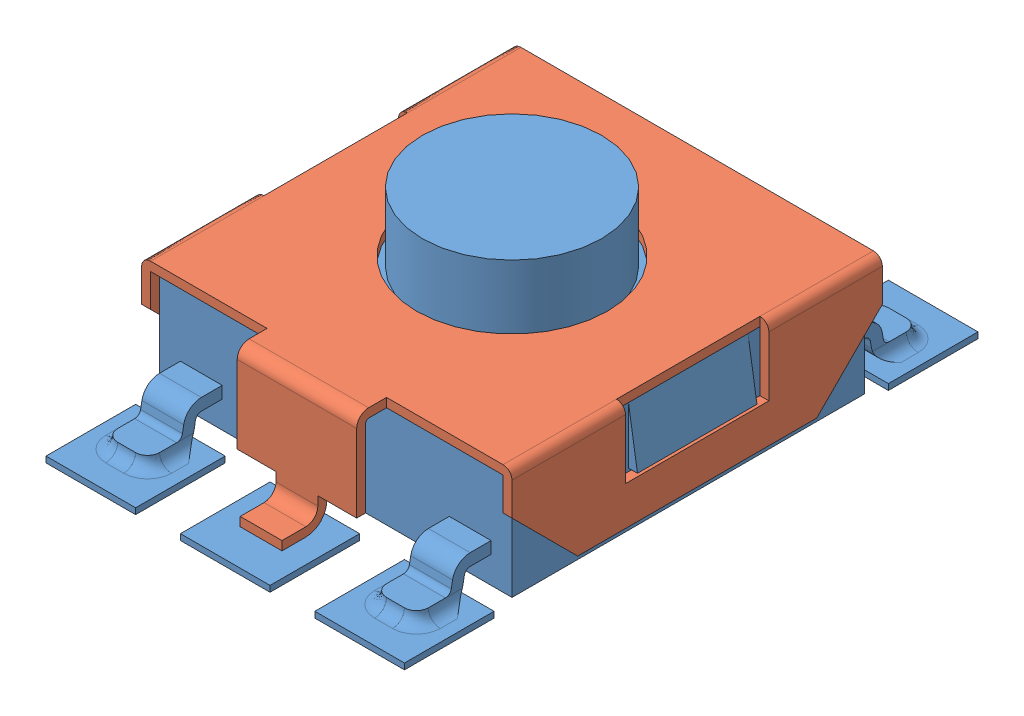
SolidWorks assembly RESET BUTTON, configuration Default. Lengths in mm.
Overall size (6.2 3.1 9.6).
2 component instances, 2 part files, 6 mates.
Components (placement in the parent):
- RESET CORE-1: RESET CORE [Default] at (0 0.1 0) x (-1 0 0) z (0 0 -1) size (6.2 3.1 9.6)
- RESET-1: RESET [Default] at (0 0.1 0) x (0 0 1) z (-1 0 0) size (7.3 2 6.2)
Mates (geometry in assembly coordinates):
- Coincident4: coincident: plane of RESET CORE-1 through (0 0.1 0) normal (0 0 -1); plane of assembly through (0 0 0) normal (0 0 1)
- Coincident5: coincident: plane of RESET CORE-1 through (0 0.1 0) normal (-1 0 0); plane of assembly through (0 0 0) normal (1 0 0)
- Coincident6: coincident: plane of RESET CORE-1 through (0 0 0) normal (0 -1 0); plane of assembly through (0 0 0) normal (0 1 0)
- Coincident7: coincident: plane of RESET-1 through (0 0.1 0) normal (0 0 1); plane of assembly through (0 0 0) normal (0 0 1)
- Coincident9: coincident: plane of RESET-1 through (0 0.1 0) normal (-1 0 0); plane of assembly
- Coincident10: coincident: plane of RESET CORE-1; plane of RESET-1
